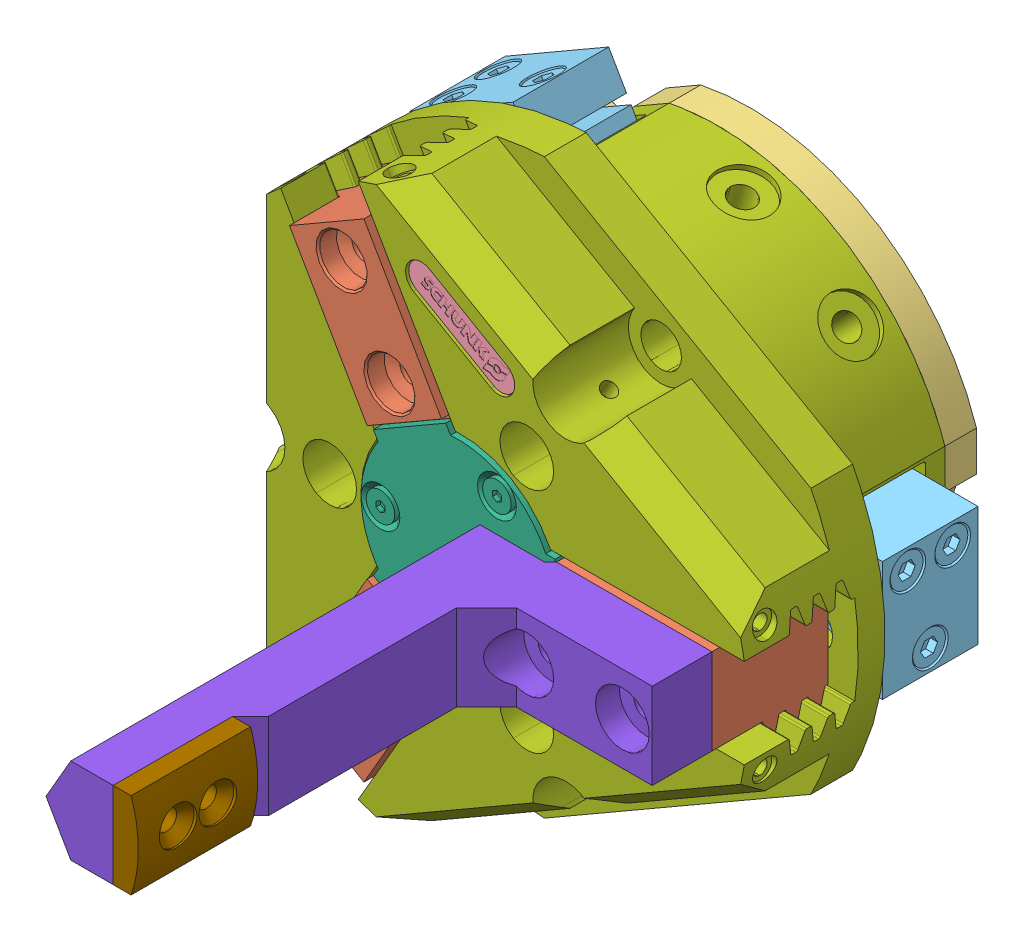
SolidWorks assembly assieme di progettazione, configuration Default. Lengths in mm.
Overall size (127.31 124.6 118.8).
13 component instances, 9 part files, 9 mates.
Components (placement in the parent):
- SCHUNK_0303311_PZN_plus_80_1__00000_3-1: SCHUNK_0303311_PZN_plus_80_1__00000_3 [Default] at (-28.9242 -13.7533 26.9) x (0.374607 -0.927184 0) z (0 0 -1) size (3.8 2.96 5)
- SCHUNK_0303311_PZN_plus_80_1__00000_5-1: SCHUNK_0303311_PZN_plus_80_1__00000_5 [Default] at (-2.1 -3.6373 29.9) x (0.866025 -0.5 0) z (-0.5 -0.866025 0) size (21.07 19.4 38.8)
- SCHUNK_0303311_PZN_plus_80_1__00000_5-2: SCHUNK_0303311_PZN_plus_80_1__00000_5 [Default] at (-2.1 3.6373 29.9) x (-0.866025 -0.5 0) z (-0.5 0.866025 0) size (21.07 19.4 38.8)
- SCHUNK_0303311_PZN_plus_80_1__00000_5-3: SCHUNK_0303311_PZN_plus_80_1__00000_5 [Default] at (4.2 0 29.9) x (0 1 0) z (1 0 0) size (21.07 19.4 38.8)
- SCHUNK_0303311_PZN_plus_80_1__00000_9-1: SCHUNK_0303311_PZN_plus_80_1__00000_9 [Default] at (0 0 5.3) x (0.866025 -0.5 0) z (0.5 0.866025 0) size (80 5.3 78)
- SCHUNK_0303311_PZN_plus_80_1__00000_11-1: SCHUNK_0303311_PZN_plus_80_1__00000_11 [Default] at (-0.1613 32.0206 47.6) x (0.866025 -0.5 0) z (0 0 1) size (20 5 0.3)
- SCHUNK_0303311_PZN_plus_80_1__00000_13-1: SCHUNK_0303311_PZN_plus_80_1__00000_13 [Default] at (35 0 8.75) x (1 0 0) z (0 -1 0) size (12 16 20)
- SCHUNK_0303311_PZN_plus_80_1__00000_13-2: SCHUNK_0303311_PZN_plus_80_1__00000_13 [Default] at (-17.5 -30.3109 8.75) x (-0.5 -0.866025 0) z (-0.866025 0.5 0) size (12 16 20)
- SCHUNK_0303311_PZN_plus_80_1__00000_13-3: SCHUNK_0303311_PZN_plus_80_1__00000_13 [Default] at (-17.5 30.3109 8.75) x (-0.5 0.866025 0) z (0.866025 0.5 0) size (12 16 20)
- SCHUNK_0303311_PZN_plus_80_1__00000_17-1: SCHUNK_0303311_PZN_plus_80_1__00000_17 [Default] at (0 0 47.3) x (0.5 0.866025 0) z (0.866025 -0.5 0) size (32.5 1.5 35.15)
- SCHUNK_0303311_PZN_plus_80_1__00000_19-1: SCHUNK_0303311_PZN_plus_80_1__00000_19 [Default] at (0 0 5.3) x (-0.866025 0.5 0) z (0.5 0.866025 0) size (95.91 43 88.5)
- Chela-1: Chela [Default] at (-0.1547 0 118.8) x (0 -1 0) z (0 0 -1) size (14.4 42 72.6)
- Gommino-1: Gommino [Default] at (-0.1547 0 118.8) x (0 1 0) z (0 0 1) size (14.4 4.21 20)
Mates (geometry in assembly coordinates):
- Parallelo1: parallel aligned: plane of SCHUNK_0303311_PZN_plus_80_1__00000_17-1 through (0 0 48.8) normal (0 0 1); plane of Chela-1 through (-0.1547 0 118.8) normal (0 0 1)
- Distanza1: distance = 1 mm: line of Chela-1 through (1 0 50.3) axis (0 0 1)
- Parallelo3: parallel aligned: plane of SCHUNK_0303311_PZN_plus_80_1__00000_5-3 through (43 -10.135 39.6205) normal (1 0 0); plane of Chela-1 through (15.2453 0 78.8) normal (1 0 0)
- Coincidente7: coincident aligned: plane of SCHUNK_0303311_PZN_plus_80_1__00000_5-3 through (43 -7.2 49.3) normal (0 -1 0); plane of Chela-1 through (-0.1547 -7.2 98.8) normal (0 -1 0)
- Distanza2: distance = 70 mm aligned: plane of Chela-1 through (-0.1547 0 118.8) normal (0 0 1); plane of SCHUNK_0303311_PZN_plus_80_1__00000_17-1 through (0 0 48.8) normal (0 0 1)
- SulPosto2: in place: plane of ? through (-0.1547 0 108.8) normal (0 0 1); plane of ? through (0 0 108.8) normal (0 0 1); moOrthogonalPlaneRef_w of ? through (-0.1547 0 108.8) normal (0 0 1); plane of ? through (0 0 108.8) normal (0 1 0); plane of ? through (-0.1547 0 108.8) normal (0 0 1); plane of ? through (0 0 108.8) normal (1 0 0); plane of Chela-1 through (-0.1547 0 118.8) normal (0 0 1); unknown of Gommino-1
- Coincidente12: coincident aligned: plane of ?; plane of ?
- Coincidente13: coincident aligned: moOrthogonalPlaneRef_w of Chela-1 through (-0.1547 0 118.8) normal (-1 0 0); plane of Parte3^SCHUNK_0303311_PZN_plus_80_1__00000-1 through (-0.1547 0 118.8) normal (-1 0 0)
- Coincidente14: coincident anti-aligned: moOrthogonalPlaneRef_w of Chela-1 through (-0.1547 0 118.8) normal (0 -1 0); plane of Parte3^SCHUNK_0303311_PZN_plus_80_1__00000-1 through (-0.1547 0 118.8) normal (0 1 0)
